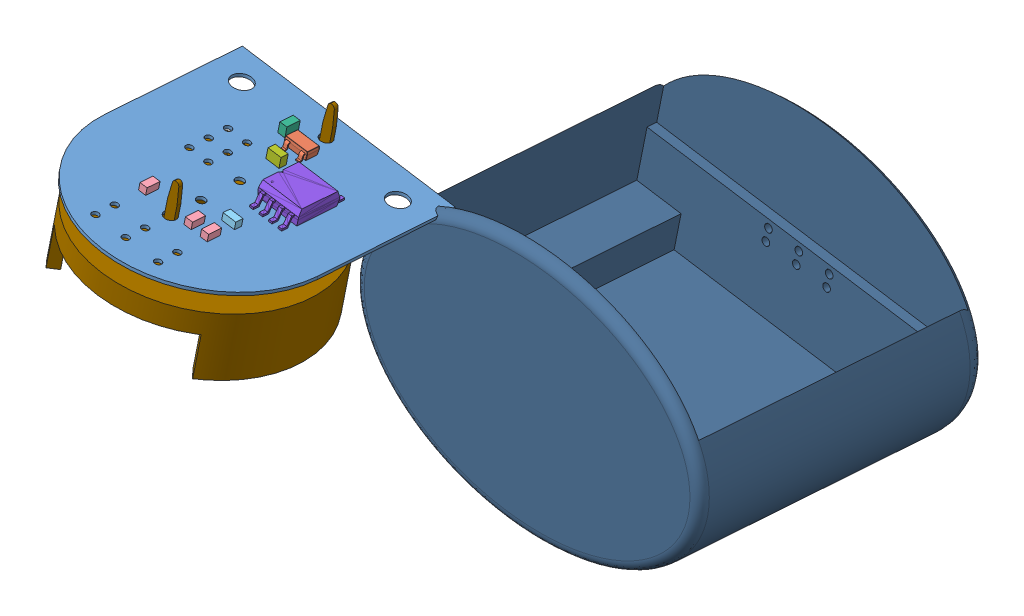
SolidWorks assembly Assem22, configuration Default. Lengths in mm.
Overall size (69.99 46.48 69.19).
29 component instances, 10 part files, 2 mates.
Components (placement in the parent):
- Flashlight PCB 2-1: Flashlight PCB 2 [Default] at (-29.3474 14.8283 66.528) x (0.989825 -0.141945 0.009893) z (0.142289 0.98743 -0.068818) size (28.59 32.39 17.34)
  - Board-1: Board [Default] at origin size (28.59 32.39 0.41)
  - U1-1: U1 [Default] at origin size (3.01 2.91 1.23)
    - SOT23-3-1: SOT23-3 [Default] at (15.3909 26.7763 0) x (0 -1 0) z (0 0 1) size (2.91 3.01 1.23)
    - 4438511424-1: 4438511424 [Default] at (15.494 27.051 0) size (0.25 0.25 0.25)
      - Extruded-1: Extruded [Default] at origin size (0.25 0.25 0.25)
  - R3-1: R3 [Default] at origin size (0.95 1.7 0.9)
    - 4438511040-1: 4438511040 [Default] at (19.685 10.656 0) size (0.95 1.7 0.9)
      - Extruded_2-1: Extruded_2 [Default] at origin size (0.95 1.7 0.9)
  - R2-1: R2 [Default] at origin size (0.95 1.7 0.9)
    - 4438511040-1: 4438511040 [Default] at (17.526 10.656 0) size (0.95 1.7 0.9)
      - Extruded_2-1: Extruded_2 [Default] at origin size (0.95 1.7 0.9)
  - R1-1: R1 [Default] at origin size (0.95 1.7 0.9)
    - 4438511040-1: 4438511040 [Default] at (11.442 10.656 0) size (0.95 1.7 0.9)
      - Extruded_2-1: Extruded_2 [Default] at origin size (0.95 1.7 0.9)
  - R4-1: R4 [Default] at origin size (1.7 0.95 0.9)
    - 4438510848-1: 4438510848 [Default] at (19.443 13.716 0) size (1.7 0.95 0.9)
      - Extruded_3-1: Extruded_3 [Default] at origin size (1.7 0.95 0.9)
  - C2-1: C2 [Default] at origin size (0.95 1.75 1.3)
    - 4438511232-1: 4438511232 [Default] at (12.7 27.748 0) size (0.95 1.75 1.3)
      - Extruded_4-1: Extruded_4 [Default] at origin size (0.95 1.75 1.3)
  - C1-1: C1 [Default] at origin size (1.75 0.95 1.3)
    - 4438510656-1: 4438510656 [Default] at (15.24 23.684 0) size (1.75 0.95 1.3)
      - Extruded_5-1: Extruded_5 [Default] at origin size (1.75 0.95 1.3)
  - ATTiny85-1: ATTiny85 [Default] at origin size (5.36 8.25 2.16)
    - 8S2-1: 8S2 [Default] at (20.8151 20.955 0) x (0 1 0) z (0 0 1) size (8.25 5.36 2.16)
  - Imported-1: Imported [Default] at origin size (27.76 30.96 17.34)
    - keystone-PN1025-7-1: keystone-PN1025-7 [Default] at (15.3925 15.0498 -2.9515) x (1 0 0) z (0 1 0) size (27.76 17.34 30.96)
- Bottom-1: Bottom [Default] at (12.8142 -7.2161 -0.8093) x (0.989825 -0.141945 0.009893) z (0 0.069525 0.99758) size (49.79 34.13 38.86)
Mates (geometry in assembly coordinates):
- Parallel3: parallel aligned: plane of Flashlight PCB 2-1/Board-1 through (-28.351 13.6244 51.3141) normal (0.142289 0.98743 -0.068818); plane of Bottom-1 through (12.1637 -11.7306 -0.4947) normal (0.142289 0.98743 -0.068818)
- Coincident5: coincident aligned: plane of Flashlight PCB 2-1/Board-1 through (-28.2746 11.9552 33.5008) normal (0 -0.069525 -0.99758); plane of Bottom-1 through (12.8142 -4.7438 34.6646) normal (0 -0.069525 -0.99758)
